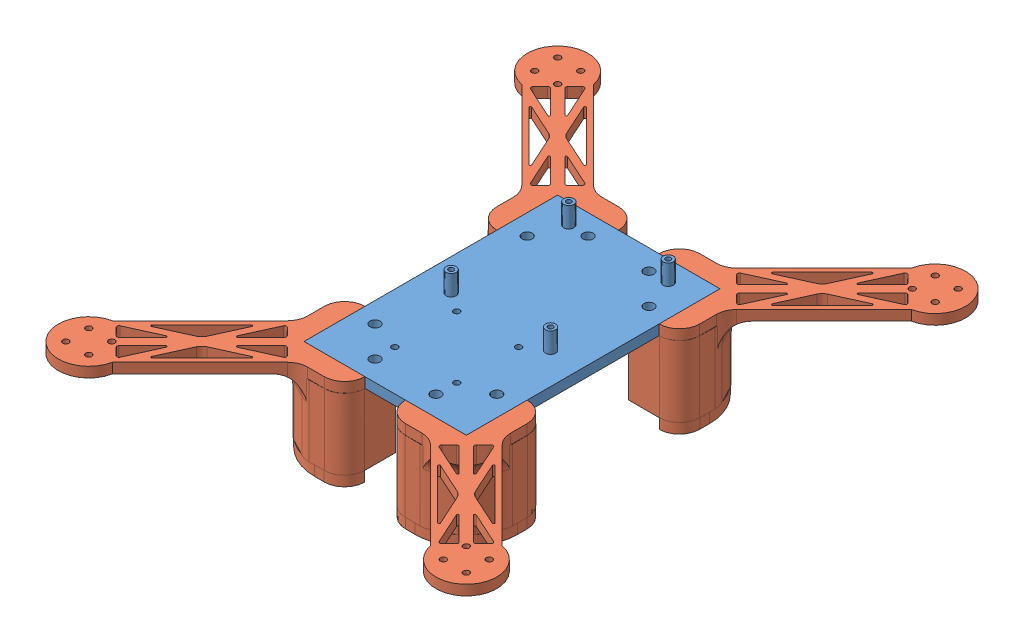
SolidWorks assembly NewAssembly, configuration Default. Lengths in mm.
Overall size (241.5 55 286.5).
5 component instances, 2 part files, 12 mates.
Components (placement in the parent):
- NewBasePlate-1: NewBasePlate [Default] at (35.2429 62.2986 98.8698) size (80 15 125)
- NewArm-1: NewArm [Default] at (75.2429 62.2986 36.3698) x (0.707107 0 -0.707107) z (0.707107 0 0.707107) size (121.82 45 48.4)
- NewArm-2: NewArm [Default] at (75.2429 62.2986 161.3698) x (0.707107 0 0.707107) z (-0.707107 0 0.707107) size (121.82 45 48.4)
- NewArm-3: NewArm [Default] at (-4.7571 62.2986 36.3698) x (-0.707107 0 -0.707107) z (0.707107 0 -0.707107) size (121.82 45 48.4)
- NewArm-4: NewArm [Default] at (-4.7571 62.2986 161.3698) x (-0.707107 0 0.707107) z (-0.707107 0 -0.707107) size (121.82 45 48.4)
Mates (geometry in assembly coordinates):
- Coincident1: coincident anti-aligned: plane of NewBasePlate-1 through (35.2429 62.2986 98.8698) normal (0 -1 0); plane of NewArm-1 through (55.2429 62.2986 36.2932) normal (0 1 0)
- Coincident2: coincident anti-aligned: plane of NewBasePlate-1 through (-4.7571 67.2986 36.3698) normal (0 0 -1); plane of NewArm-1 through (75.2429 67.2986 36.3698) normal (0 0 1)
- Coincident3: coincident anti-aligned: plane of NewBasePlate-1 through (75.2429 67.2986 161.3698) normal (1 0 0); plane of NewArm-1 through (75.2429 67.2986 36.3698) normal (-1 0 0)
- Coincident4: coincident anti-aligned: plane of NewBasePlate-1 through (35.2429 62.2986 98.8698) normal (0 -1 0); plane of NewArm-3 through (-4.8337 62.2986 56.3698) normal (0 1 0)
- Coincident5: coincident anti-aligned: plane of NewBasePlate-1 through (35.2429 62.2986 98.8698) normal (0 -1 0); plane of NewArm-4 through (15.2429 62.2986 161.4464) normal (0 1 0)
- Coincident6: coincident anti-aligned: plane of NewBasePlate-1 through (35.2429 62.2986 98.8698) normal (0 -1 0); plane of NewArm-2 through (75.3195 62.2986 141.3698) normal (0 1 0)
- Coincident7: coincident anti-aligned: plane of NewBasePlate-1 through (75.2429 67.2986 161.3698) normal (1 0 0); plane of NewArm-2 through (75.2429 67.2986 161.3698) normal (-1 0 0)
- Coincident8: coincident anti-aligned: plane of NewBasePlate-1 through (-4.7571 67.2986 161.3698) normal (0 0 1); plane of NewArm-2 through (75.2429 67.2986 161.3698) normal (0 0 -1)
- Coincident9: coincident anti-aligned: plane of NewBasePlate-1 through (-4.7571 67.2986 36.3698) normal (0 0 -1); plane of NewArm-3 through (-4.7571 67.2986 36.3698) normal (0 0 1)
- Coincident10: coincident anti-aligned: plane of NewBasePlate-1 through (-4.7571 67.2986 161.3698) normal (-1 0 0); plane of NewArm-3 through (-4.7571 67.2986 36.3698) normal (1 0 0)
- Coincident11: coincident anti-aligned: plane of NewBasePlate-1 through (-4.7571 67.2986 161.3698) normal (0 0 1); plane of NewArm-4 through (-4.7571 67.2986 161.3698) normal (0 0 -1)
- Coincident13: coincident anti-aligned: plane of NewBasePlate-1 through (-4.7571 67.2986 161.3698) normal (-1 0 0); plane of NewArm-4 through (-4.7571 67.2986 161.3698) normal (1 0 0)
